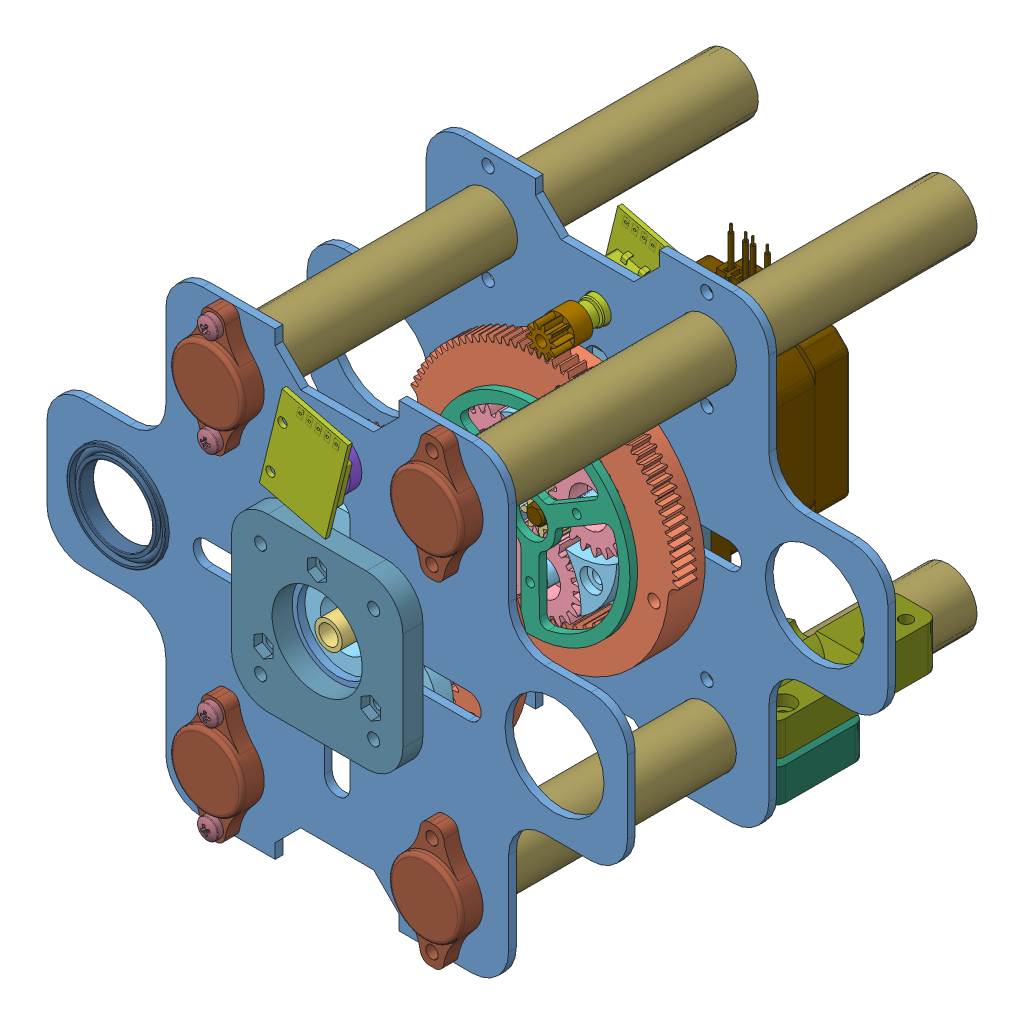
SolidWorks assembly CaderaEnsamble, configuration Predeterminado. Lengths in mm.
Overall size (159.22 126.22 146.31).
44 component instances, 19 part files, 49 mates.
Components (placement in the parent):
- CSF_SoporteFrontalDeCadera-1: CSF_SoporteFrontalDeCadera [Predeterminado] at origin size (159.22 126 2.11)
- CSF_SoporteFrontalDeCadera-2: CSF_SoporteFrontalDeCadera [Predeterminado] at (0 0 -71.39) size (159.22 126 2.11)
- ReductorDeCaderaEsnamble-1: ReductorDeCaderaEsnamble [Predeterminado] at (0 0 -69.28) x (0.506756 -0.86209 0) z (-0.86209 -0.506756 0) size (103.58 23.11 103.81)
  - AnilloCompatibleEncoder-3: AnilloCompatibleEncoder [Predeterminado] at (0 10.5 0) x (0 1 0) z (-0.638564 0 0.769569) size (10 72.79 74.49)
  - sol-2: sol [ISO - Spur gear 1M 10T 20PA 10FW ---S10A75H50L0.8N] at (0 5.5 0) x (0 1 0) z (0.86534 0 0.501185) size (20 11.48 12)
  - Planeta-10: Planeta [ISO - Spur gear 1M 20T 20PA 10FW ---S20A75H50L0.8N] at (0 5.5 -15) x (0 1 0) z (-0.10816 0 -0.994133) size (10 21.8 21.8)
  - Planeta-11: Planeta [ISO - Spur gear 1M 20T 20PA 10FW ---S20A75H50L0.8N] at (-12.9904 5.5 7.5) x (0 1 0) z (0.409408 0 0.912351) size (10 21.8 21.8)
  - Planeta-12: Planeta [ISO - Spur gear 1M 20T 20PA 10FW ---S20A75H50L0.8N] at (12.9904 5.5 7.5) x (0 1 0) z (0.993343 0 -0.115196) size (10 21.8 21.8)
  - PortaPlanetas-1: PortaPlanetas [Predeterminado] at origin size (50.52 16.5 49.09)
  - TapaDeportaPlanetas-1: TapaDeportaPlanetas [Predeterminado] at (0 16.5 0) x (-0.5 0 0.866025) z (-0.866025 0 -0.5) size (55 2.11 55)
- Encoder KY-040modificadoCadera-1: Encoder KY-040modificadoCadera [Default] at (1.7355 43.0573 -80.19) x (-0.9712 0.238268 0) z (0.238268 0.9712 0) size (18.6 18.94 26.2)
- separadorDeEncoder_Cadera-1: separadorDeEncoder_Cadera [Predeterminado] at (0 40.6 -74.59) size (13.5 13.5 3.2)
- EngraneParaEncoder-1: EngraneParaEncoder [ISO - Spur gear 0.7M 10T 20PA 5FW ---S10A75H50L3.0N] at (0 40.6 -58.78) x (0 0 1) z (-0.44596 0.895053 0) size (10 8.5 8.5)
- angular contact ball bearing_68_iso-4: angular contact ball bearing_68_iso [ISO 15 ABB - 1720 - 28,SI,NC,28_68] at (-59.61 0 1.1962) x (0 0 -1) z (0.998827 -0.048426 0) size (4 27 27)
- Acoplador de tubo con cadera exterior-1: Acoplador de tubo con cadera exterior [Predeterminado] at (-30 46 -5.39) x (0 0 1) z (-1 0 0) size (21 34 20)
- TuboOpcion2-1: TuboOpcion2 [Predeterminado] at (-30 46 4.61) x (-0.461463 0.887159 0) z (-0.887159 -0.461463 0) size (16 140 16)
- TuboOpcion2-2: TuboOpcion2 [Predeterminado] at (30 46 4.61) x (0.461463 0.887159 0) z (-0.887159 0.461463 0) size (16 140 16)
- Acoplador de tubo con cadera exterior-2: Acoplador de tubo con cadera exterior [Predeterminado] at (30 46 -5.39) x (0 0 1) z (-1 0 0) size (21 34 20)
- pan head cross recess screw_iso-1: pan head cross recess screw_iso [ISO 7045 - M3 x 8 - Z - 8N] at (-30 32.5 8.51) x (0 0 -1) z (1 0 0) size (10.35 5.6 5.6)
- pan head cross recess screw_iso-2: pan head cross recess screw_iso [ISO 7045 - M3 x 8 - Z - 8N] at (-30 59.5 8.51) x (0 0 -1) z (0.35329 0.935514 0) size (10.35 5.6 5.6)
- AcopladorDeReductorCadera-1: AcopladorDeReductorCadera [Predeterminado] at (0 0 -71.39) x (0 0 -1) z (-1 0 0) size (5.5 47 47)
- ManivelaCadera-2: ManivelaCadera [Predeterminado] at (-54.0386 31.0034 -49.89) size (69.01 9.4 2.11) (hidden)
- ReductorDeCaderaEsnamble-2: ReductorDeCaderaEsnamble [Predeterminado] x (0.5 -0.866025 0) z (0.866025 0.5 0) size (103.58 23.11 103.81)
  - AnilloCompatibleEncoder-3: AnilloCompatibleEncoder [Predeterminado] at (0 10.5 0) x (0 1 0) z (-0.638564 0 0.769569) size (10 72.79 74.49)
  - sol-2: sol [ISO - Spur gear 1M 10T 20PA 10FW ---S10A75H50L0.8N] at (0 5.5 0) x (0 1 0) z (0.86534 0 0.501185) size (20 11.48 12)
  - Planeta-10: Planeta [ISO - Spur gear 1M 20T 20PA 10FW ---S20A75H50L0.8N] at (0 5.5 -15) x (0 1 0) z (-0.10816 0 -0.994133) size (10 21.8 21.8)
  - Planeta-11: Planeta [ISO - Spur gear 1M 20T 20PA 10FW ---S20A75H50L0.8N] at (-12.9904 5.5 7.5) x (0 1 0) z (0.409408 0 0.912351) size (10 21.8 21.8)
  - Planeta-12: Planeta [ISO - Spur gear 1M 20T 20PA 10FW ---S20A75H50L0.8N] at (12.9904 5.5 7.5) x (0 1 0) z (0.993343 0 -0.115196) size (10 21.8 21.8)
  - PortaPlanetas-1: PortaPlanetas [Predeterminado] at origin size (50.52 16.5 49.09)
  - TapaDeportaPlanetas-1: TapaDeportaPlanetas [Predeterminado] at (0 16.5 0) x (-0.5 0 0.866025) z (-0.866025 0 -0.5) size (55 2.11 55)
- TuboOpcion2-3: TuboOpcion2 [Predeterminado] at (30 -46 4.61) x (0.461463 -0.887159 0) z (0.887159 0.461463 0) size (16 140 16)
- TuboOpcion2-4: TuboOpcion2 [Predeterminado] at (-30 -46 4.61) x (-0.461463 -0.887159 0) z (0.887159 -0.461463 0) size (16 140 16)
- Acoplador de tubo con cadera exterior-3: Acoplador de tubo con cadera exterior [Predeterminado] at (30 -46 -5.39) x (0 0 1) z (1 0 0) size (21 34 20)
- Acoplador de tubo con cadera exterior-4: Acoplador de tubo con cadera exterior [Predeterminado] at (-30 -46 -5.39) x (0 0 1) z (1 0 0) size (21 34 20)
- pan head cross recess screw_iso-3: pan head cross recess screw_iso [ISO 7045 - M3 x 8 - Z - 8N] at (-30 -59.5 8.51) x (0 0 -1) z (-0.35329 0.935514 0) size (10.35 5.6 5.6)
- pan head cross recess screw_iso-4: pan head cross recess screw_iso [ISO 7045 - M3 x 8 - Z - 8N] at (-30 -32.5 8.51) x (0 0 -1) z (-1 0 0) size (10.35 5.6 5.6)
- Encoder KY-040modificadoCadera-4: Encoder KY-040modificadoCadera [Default] at (-0.4012 43.5815 10.91) x (0.9712 -0.238268 0) z (0.238268 0.9712 0) size (18.6 18.94 26.2)
- separadorDeEncoder_Cadera-2: separadorDeEncoder_Cadera [Predeterminado] at (0 40.6 5.31) x (-0.923728 -0.383049 0) z (0 0 -1) size (13.5 13.5 3.2)
- AcopladorDeReductorCadera-2: AcopladorDeReductorCadera [Predeterminado] at (0 0 2.11) x (0 0 1) z (-1 0 0) size (5.5 47 47)
- Acoplador de tubo con cuerpo inferior-1: Acoplador de tubo con cuerpo inferior [Predeterminado] at (-30 -54.5 -83.89) size (33 12 25)
- Acoplador de tubo con cuerpo-3: Acoplador de tubo con cuerpo [Predeterminado] at (30 -37.5 -83.89) x (1 0 0) z (0 0 -1) size (33 17 45)
- Acoplador de tubo con cuerpo invertido-1: Acoplador de tubo con cuerpo invertido [Predeterminado] at (-30 -37.5 -83.89) x (1 0 0) z (0 0 -1) size (33 17 45)
- Acoplador de tubo con cuerpo inferior-3: Acoplador de tubo con cuerpo inferior [Predeterminado] at (30 -54.5 -83.89) size (33 12 25)
- nema_17_motor-1: nema_17_motor [Varsayılan] at (0 0 -76.89) size (42 58.5 65.65)
Mates (geometry in assembly coordinates):
- Concéntrica1: concentric: circle of assembly; circle of assembly; circle of CSF_SoporteFrontalDeCadera-1; circle of CSF_SoporteFrontalDeCadera-2
- Concéntrica2: concentric: circle of assembly; circle of assembly; circle of CSF_SoporteFrontalDeCadera-1; circle of CSF_SoporteFrontalDeCadera-2
- Concéntrica3: concentric: circle of assembly; circle of assembly; circle of CSF_SoporteFrontalDeCadera-2; circle of ReductorDeCaderaEsnamble-1/PortaPlanetas-1
- Concéntrica4: concentric: circle of assembly; circle of assembly; circle of separadorDeEncoder_Cadera-1; circle of Encoder KY-040modificadoCadera-1
- Coincidente4: coincident: plane of assembly; plane of assembly; plane of Encoder KY-040modificadoCadera-1 through (1.7355 43.0573 -74.59) normal (0 0 1); plane of separadorDeEncoder_Cadera-1 through (0 40.6 -74.59) normal (0 0 -1)
- Concéntrica5: concentric: circle of assembly; circle of assembly; circle of CSF_SoporteFrontalDeCadera-2; circle of Encoder KY-040modificadoCadera-1
- Concéntrica6: concentric: circle of assembly; circle of assembly; circle of CSF_SoporteFrontalDeCadera-2; circle of EngraneParaEncoder-1
- Coincidente5: coincident: plane of assembly; plane of assembly; plane of CSF_SoporteFrontalDeCadera-2 through (0 0 -69.28) normal (0 0 1); plane of ReductorDeCaderaEsnamble-1/PortaPlanetas-1 through (0 0 -69.28) normal (0 0 -1)
- Relación de posición de engranaje1: gear = 74.2 : 7 mm: cylinder of assembly; cylinder of assembly; cylinder of EngraneParaEncoder-1 through (0 40.6 -68.78) axis (0 0 -1) radius 4.2; cylinder of ReductorDeCaderaEsnamble-1/AnilloCompatibleEncoder-3 through (0 0 -68.78) axis (0 0 -1) radius 37.8
- Coincidente6: coincident: plane of assembly; plane of assembly; plane of CSF_SoporteFrontalDeCadera-2 through (0 0 -71.39) normal (0 0 -1); plane of separadorDeEncoder_Cadera-1 through (0 40.6 -71.39) normal (0 0 1)
- Concéntrica9: concentric: circle of assembly; circle of assembly; circle of CSF_SoporteFrontalDeCadera-1; circle of TuboOpcion2-1
- Concéntrica10: concentric: circle of assembly; circle of assembly; circle of TuboOpcion2-1; circle of Acoplador de tubo con cadera exterior-1
- Coincidente7: coincident: plane of assembly; plane of assembly; plane of Acoplador de tubo con cadera exterior-1 through (-30 46 4.61) normal (0 0 -1); plane of TuboOpcion2-1 through (-30 46 4.61) normal (0 0 1)
- Concéntrica12: concentric: circle of assembly; circle of assembly; circle of CSF_SoporteFrontalDeCadera-1; circle of Acoplador de tubo con cadera exterior-1
- Coincidente8: coincident: plane of assembly; plane of assembly; plane of CSF_SoporteFrontalDeCadera-1 through (0 0 2.11) normal (0 0 1); plane of Acoplador de tubo con cadera exterior-1 through (-30 46 2.11) normal (0 0 -1)
- Distancia1: distance = 73.5 mm: plane of assembly; plane of assembly; plane of CSF_SoporteFrontalDeCadera-2 through (0 0 -71.39) normal (0 0 -1); plane of CSF_SoporteFrontalDeCadera-1 through (0 0 2.11) normal (0 0 1)
- Concéntrica13: concentric: cylinder of assembly; cylinder of assembly; cylinder of Acoplador de tubo con cadera exterior-1 through (-30 32.5 6.11) axis (0 0 -1) radius 1.7; cylinder of pan head cross recess screw_iso-1 through (-30 32.5 33.91) axis (0 0 1) radius 2.8
- Coincidente10: coincident: plane of assembly; plane of assembly; plane of Acoplador de tubo con cadera exterior-1 through (-30 46 6.11) normal (0 0 1); plane of pan head cross recess screw_iso-1 through (-30 34 6.11) normal (0 0 -1)
- Concéntrica14: concentric: cylinder of assembly; cylinder of assembly; cylinder of Acoplador de tubo con cadera exterior-1 through (-30 59.5 6.11) axis (0 0 -1) radius 1.7; cylinder of pan head cross recess screw_iso-2 through (-30 59.5 33.91) axis (0 0 1) radius 2.8
- Coincidente11: coincident: plane of assembly; plane of assembly; plane of Acoplador de tubo con cadera exterior-1 through (-30 46 6.11) normal (0 0 1); plane of pan head cross recess screw_iso-2 through (-31.4033 60.0299 6.11) normal (0 0 -1)
- Concéntrica18: concentric: circle of assembly; circle of assembly; circle of CSF_SoporteFrontalDeCadera-2; circle of AcopladorDeReductorCadera-1
- Concéntrica26: concentric: circle of assembly; circle of assembly; circle of ReductorDeCaderaEsnamble-1/AnilloCompatibleEncoder-3; circle of ManivelaCadera-2
- Distancia2: distance = 6 mm: plane of assembly; plane of assembly; plane of ManivelaCadera-2 through (-54.0386 31.0034 -47.78) normal (0 0 1); plane of ReductorDeCaderaEsnamble-1/AnilloCompatibleEncoder-3 through (23.6216 -4.2449 -53.78) normal (0 0 1)
- Concéntrica32: concentric: circle of assembly; circle of assembly; circle of CSF_SoporteFrontalDeCadera-1; circle of ReductorDeCaderaEsnamble-2/PortaPlanetas-1
- Coincidente21: coincident: plane of assembly; plane of assembly; plane of CSF_SoporteFrontalDeCadera-1 through (0 0 0) normal (0 0 -1); plane of ReductorDeCaderaEsnamble-2/PortaPlanetas-1 through (0 0 0) normal (0 0 1)
- Concéntrica33: concentric: circle of assembly; circle of assembly; circle of CSF_SoporteFrontalDeCadera-1; circle of ReductorDeCaderaEsnamble-2/PortaPlanetas-1
- Concéntrica34: concentric: circle of assembly; circle of assembly; circle of Encoder KY-040modificadoCadera-4; circle of separadorDeEncoder_Cadera-2
- Coincidente22: coincident: plane of assembly; plane of assembly; plane of Encoder KY-040modificadoCadera-4 through (-0.4012 43.5815 5.31) normal (0 0 -1); plane of separadorDeEncoder_Cadera-2 through (0 40.6 5.31) normal (0 0 1)
- Concéntrica35: concentric: circle of assembly; circle of assembly; circle of CSF_SoporteFrontalDeCadera-1; circle of Encoder KY-040modificadoCadera-4
- Coincidente23: coincident: plane of assembly; plane of assembly; plane of CSF_SoporteFrontalDeCadera-1 through (0 0 2.11) normal (0 0 1); plane of separadorDeEncoder_Cadera-2 through (0 40.6 2.11) normal (0 0 -1)
- Paralelo1: parallel: plane of assembly; plane of assembly; plane of Encoder KY-040modificadoCadera-1 through (7.3539 44.9738 -74.59) normal (0.238268 0.9712 0); plane of Encoder KY-040modificadoCadera-4 through (-4.4947 47.8806 5.31) normal (0.238268 0.9712 0)
- Concéntrica37: concentric: circle of assembly; circle of assembly; circle of CSF_SoporteFrontalDeCadera-1; circle of AcopladorDeReductorCadera-2
- Coincidente25: coincident: plane of assembly; plane of assembly; plane of CSF_SoporteFrontalDeCadera-1 through (0 0 2.11) normal (0 0 1); plane of AcopladorDeReductorCadera-2 through (0 0 2.11) normal (0 0 -1)
- Concéntrica39: concentric: circle of assembly; circle of assembly; circle of CSF_SoporteFrontalDeCadera-1; circle of AcopladorDeReductorCadera-2
- Concéntrica42: concentric: circle of assembly; circle of assembly; circle of CSF_SoporteFrontalDeCadera-2; circle of Acoplador de tubo con cuerpo inferior-1
- Coincidente272: coincident: plane of assembly; plane of assembly; plane of CSF_SoporteFrontalDeCadera-2 through (0 0 -71.39) normal (0 0 -1); plane of Acoplador de tubo con cuerpo inferior-1 through (-30 -46 -71.39) normal (0 0 1)
- Concéntrica43: concentric: circle of assembly; circle of assembly; circle of CSF_SoporteFrontalDeCadera-2; circle of Acoplador de tubo con cuerpo-3
- Coincidente273: coincident: plane of assembly; plane of assembly; plane of CSF_SoporteFrontalDeCadera-2 through (0 0 -71.39) normal (0 0 -1); plane of Acoplador de tubo con cuerpo-3 through (30 -46 -71.39) normal (0 0 1)
- Concéntrica45: concentric: circle of assembly; circle of assembly; circle of CSF_SoporteFrontalDeCadera-2; circle of Acoplador de tubo con cuerpo invertido-1
- Coincidente274: coincident: plane of assembly; plane of assembly; plane of CSF_SoporteFrontalDeCadera-2 through (0 0 -71.39) normal (0 0 -1); plane of Acoplador de tubo con cuerpo invertido-1 through (-30 -46 -71.39) normal (0 0 1)
- Concéntrica46: concentric: circle of assembly; circle of assembly; circle of Acoplador de tubo con cuerpo inferior-1; circle of Acoplador de tubo con cuerpo invertido-1
- Paralelo2: parallel: plane of assembly; plane of assembly; plane of CSF_SoporteFrontalDeCadera-2 through (-79.61 20 -13.2697) normal (0 1 0); plane of Acoplador de tubo con cuerpo invertido-1 through (-46.5 -33 -116.39) normal (0 1 0)
- Concéntrica47: concentric: circle of assembly; circle of assembly; circle of CSF_SoporteFrontalDeCadera-2; circle of Acoplador de tubo con cuerpo inferior-3
- Coincidente276: coincident: plane of assembly; plane of assembly; plane of CSF_SoporteFrontalDeCadera-2 through (0 0 -71.39) normal (0 0 -1); plane of Acoplador de tubo con cuerpo inferior-3 through (30 -46 -71.39) normal (0 0 1)
- Concéntrica48: concentric: circle of assembly; circle of assembly; circle of CSF_SoporteFrontalDeCadera-2; circle of AcopladorDeReductorCadera-1
- Coincidente277: coincident: plane of assembly; plane of assembly; plane of CSF_SoporteFrontalDeCadera-2 through (0 0 -71.39) normal (0 0 -1); plane of AcopladorDeReductorCadera-1 through (0 0 -71.39) normal (0 0 1)
- Concéntrica49: concentric: circle of assembly; circle of assembly; circle of CSF_SoporteFrontalDeCadera-2; circle of nema_17_motor-1
- Concéntrica50: concentric: circle of assembly; circle of assembly; circle of AcopladorDeReductorCadera-1; circle of nema_17_motor-1
- Coincidente278: coincident: plane of assembly; plane of assembly; plane of AcopladorDeReductorCadera-1 through (0 0 -76.89) normal (0 0 -1); plane of nema_17_motor-1 through (0 0 -76.89) normal (0 0 1)
